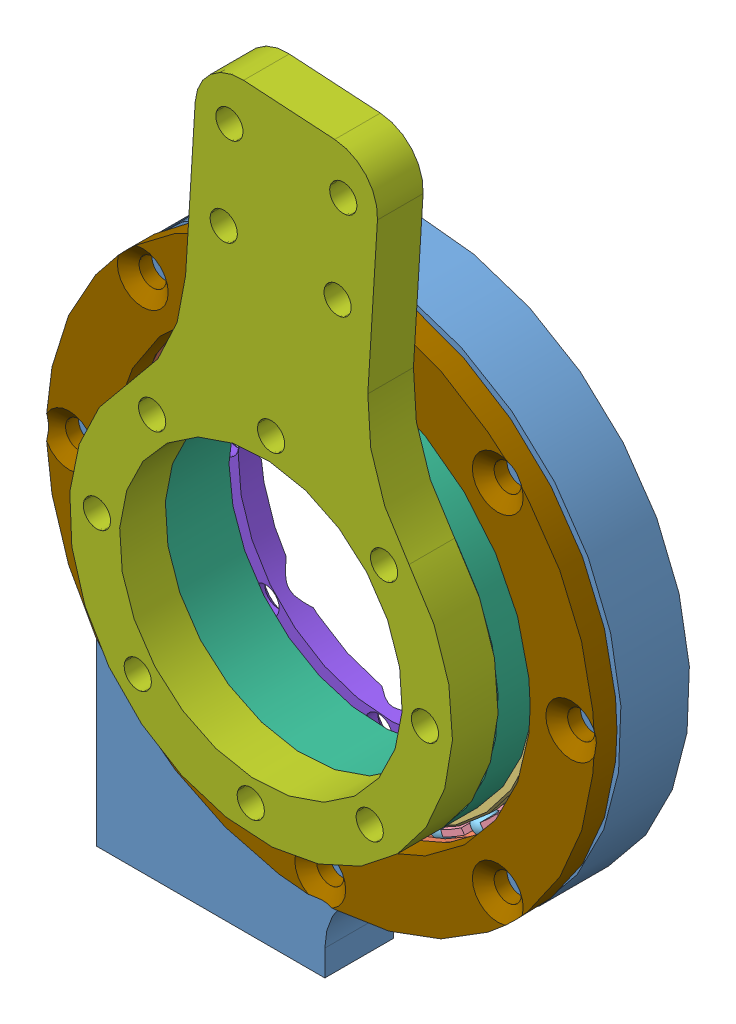
SolidWorks assembly shoulder-bearing-half, configuration otherside. Lengths in mm.
Overall size (78.52 115.83 21.59).
37 component instances, 9 part files, 14 mates.
Components (placement in the parent):
- a01-shoulder-base-1: a01-shoulder-base [otherside] at origin size (76.2 88.9 6.35)
- SW3dPS partNO- -KA020AR0-1: SW3dPS partNO- -KA020AR0 [KA020CP0] at (0 0 7.3406) x (-1 0 0) z (0 -1 0) size (63.5 6.35 63.5)
  - SW3dPS-KA - Radial Contact_KA OUTER CATALOG-1: SW3dPS-KA - Radial Contact_KA OUTER CATALOG [KA020002] at origin size (63.5 6.35 63.5)
  - SW3dPS-KA - Radial Contact_KA INNER CATALOG-1: SW3dPS-KA - Radial Contact_KA INNER CATALOG [KA020003] at origin size (55.52 6.35 55.52)
  - SW3dPS-KA - Radial Contact_KA SEPARATOR SAMPLE-1: SW3dPS-KA - Radial Contact_KA SEPARATOR SAMPLE [KA020] at origin size (60.31 5.28 60.41)
    - SW3dPS-KA - Radial Contact_KA SEPARATOR SAMPLE-1: SW3dPS-KA - Radial Contact_KA SEPARATOR SAMPLE [02510020] at origin size (57.94 5.28 57.94)
    - SW3dPS-KA - Radial Contact_KA BALL-1: SW3dPS-KA - Radial Contact_KA BALL [KA020] at origin size (3.17 3.17 3.17)
    - SW3dPS-KA - Radial Contact_KA BALL-2: SW3dPS-KA - Radial Contact_KA BALL [KA020] x (0.973045 0 0.230616) z (-0.230616 0 0.973045) size (3.17 3.17 3.17)
    - SW3dPS-KA - Radial Contact_KA BALL-3: SW3dPS-KA - Radial Contact_KA BALL [KA020] x (0.893633 0 0.448799) z (-0.448799 0 0.893633) size (3.17 3.17 3.17)
    - SW3dPS-KA - Radial Contact_KA BALL-4: SW3dPS-KA - Radial Contact_KA BALL [KA020] x (0.766044 0 0.642788) z (-0.642788 0 0.766044) size (3.17 3.17 3.17)
    - SW3dPS-KA - Radial Contact_KA BALL-5: SW3dPS-KA - Radial Contact_KA BALL [KA020] x (0.597159 0 0.802123) z (-0.802123 0 0.597159) size (3.17 3.17 3.17)
    - SW3dPS-KA - Radial Contact_KA BALL-6: SW3dPS-KA - Radial Contact_KA BALL [KA020] x (0.39608 0 0.918216) z (-0.918216 0 0.39608) size (3.17 3.17 3.17)
    - SW3dPS-KA - Radial Contact_KA BALL-7: SW3dPS-KA - Radial Contact_KA BALL [KA020] x (0.173648 0 0.984808) z (-0.984808 0 0.173648) size (3.17 3.17 3.17)
    - SW3dPS-KA - Radial Contact_KA BALL-8: SW3dPS-KA - Radial Contact_KA BALL [KA020] x (-0.058145 0 0.998308) z (-0.998308 0 -0.058145) size (3.17 3.17 3.17)
    - SW3dPS-KA - Radial Contact_KA BALL-9: SW3dPS-KA - Radial Contact_KA BALL [KA020] x (-0.286803 0 0.95799) z (-0.95799 0 -0.286803) size (3.17 3.17 3.17)
    - SW3dPS-KA - Radial Contact_KA BALL-10: SW3dPS-KA - Radial Contact_KA BALL [KA020] x (-0.5 0 0.866025) z (-0.866025 0 -0.5) size (3.17 3.17 3.17)
    - SW3dPS-KA - Radial Contact_KA BALL-11: SW3dPS-KA - Radial Contact_KA BALL [KA020] x (-0.686242 0 0.727374) z (-0.727374 0 -0.686242) size (3.17 3.17 3.17)
    - SW3dPS-KA - Radial Contact_KA BALL-12: SW3dPS-KA - Radial Contact_KA BALL [KA020] x (-0.835488 0 0.549509) z (-0.549509 0 -0.835488) size (3.17 3.17 3.17)
    - SW3dPS-KA - Radial Contact_KA BALL-13: SW3dPS-KA - Radial Contact_KA BALL [KA020] x (-0.939693 0 0.34202) z (-0.34202 0 -0.939693) size (3.17 3.17 3.17)
    - SW3dPS-KA - Radial Contact_KA BALL-14: SW3dPS-KA - Radial Contact_KA BALL [KA020] x (-0.993238 0 0.116093) z (-0.116093 0 -0.993238) size (3.17 3.17 3.17)
    - SW3dPS-KA - Radial Contact_KA BALL-15: SW3dPS-KA - Radial Contact_KA BALL [KA020] x (-0.993238 0 -0.116093) z (0.116093 0 -0.993238) size (3.17 3.17 3.17)
    - SW3dPS-KA - Radial Contact_KA BALL-16: SW3dPS-KA - Radial Contact_KA BALL [KA020] x (-0.939693 0 -0.34202) z (0.34202 0 -0.939693) size (3.17 3.17 3.17)
    - SW3dPS-KA - Radial Contact_KA BALL-17: SW3dPS-KA - Radial Contact_KA BALL [KA020] x (-0.835488 0 -0.549509) z (0.549509 0 -0.835488) size (3.17 3.17 3.17)
    - SW3dPS-KA - Radial Contact_KA BALL-18: SW3dPS-KA - Radial Contact_KA BALL [KA020] x (-0.686242 0 -0.727374) z (0.727374 0 -0.686242) size (3.17 3.17 3.17)
    - SW3dPS-KA - Radial Contact_KA BALL-19: SW3dPS-KA - Radial Contact_KA BALL [KA020] x (-0.5 0 -0.866025) z (0.866025 0 -0.5) size (3.17 3.17 3.17)
    - SW3dPS-KA - Radial Contact_KA BALL-20: SW3dPS-KA - Radial Contact_KA BALL [KA020] x (-0.286803 0 -0.95799) z (0.95799 0 -0.286803) size (3.17 3.17 3.17)
    - SW3dPS-KA - Radial Contact_KA BALL-21: SW3dPS-KA - Radial Contact_KA BALL [KA020] x (-0.058145 0 -0.998308) z (0.998308 0 -0.058145) size (3.17 3.17 3.17)
    - SW3dPS-KA - Radial Contact_KA BALL-22: SW3dPS-KA - Radial Contact_KA BALL [KA020] x (0.173648 0 -0.984808) z (0.984808 0 0.173648) size (3.17 3.17 3.17)
    - SW3dPS-KA - Radial Contact_KA BALL-23: SW3dPS-KA - Radial Contact_KA BALL [KA020] x (0.39608 0 -0.918216) z (0.918216 0 0.39608) size (3.17 3.17 3.17)
    - SW3dPS-KA - Radial Contact_KA BALL-24: SW3dPS-KA - Radial Contact_KA BALL [KA020] x (0.597159 0 -0.802123) z (0.802123 0 0.597159) size (3.17 3.17 3.17)
    - SW3dPS-KA - Radial Contact_KA BALL-25: SW3dPS-KA - Radial Contact_KA BALL [KA020] x (0.766044 0 -0.642788) z (0.642788 0 0.766044) size (3.17 3.17 3.17)
    - SW3dPS-KA - Radial Contact_KA BALL-26: SW3dPS-KA - Radial Contact_KA BALL [KA020] x (0.893633 0 -0.448799) z (0.448799 0 0.893633) size (3.17 3.17 3.17)
    - SW3dPS-KA - Radial Contact_KA BALL-27: SW3dPS-KA - Radial Contact_KA BALL [KA020] x (0.973045 0 -0.230616) z (0.230616 0 0.973045) size (3.17 3.17 3.17)
- a02-inside-bearing-1: a02-inside-bearing [Default] at (0 0 15.24) x (0 0 1) z (-0.061832 -0.998087 0)
- a04-shoulder-output-1: a04-shoulder-output [Default] at (0 0 21.59) x (0.998087 -0.061832 0) z (0 0 -1)
- a08-innerbearing-ring-1: a08-innerbearing-ring [Default] at (0 0 3.81) x (-0.662032 0.749475 0) z (0 0 -1)
- a07-outerbearing-ring-1: a07-outerbearing-ring [Default] at (0 0 10.16)
Mates (geometry in assembly coordinates):
- Coincident1: coincident anti-aligned: plane of a01-shoulder-base-1; plane of SW3dPS partNO- -KA020AR0-1/SW3dPS-KA - Radial Contact_KA OUTER CATALOG-1
- Concentric1: concentric aligned: cylinder of a01-shoulder-base-1; cylinder of ?
- Coincident2: coincident anti-aligned: plane of ?; plane of a02-inside-bearing-1 through (-26.619 1.649 10.16) normal (0 0 -1)
- Concentric2: concentric anti-aligned: cylinder of ?; cylinder of a02-inside-bearing-1
- Concentric3: concentric aligned: cylinder of a02-inside-bearing-1; cylinder of a04-shoulder-output-1
- Coincident3: coincident anti-aligned: plane of a02-inside-bearing-1 through (-20.9149 1.2957 15.24) normal (0 0 1); plane of a04-shoulder-output-1 through (0 0 15.24) normal (0 0 -1)
- Parallel1: parallel anti-aligned: plane of a01-shoulder-base-1; plane of ?
- Concentric4: concentric aligned: cylinder of a02-inside-bearing-1; cylinder of a04-shoulder-output-1
- Concentric5: concentric aligned: cylinder of a02-inside-bearing-1; cylinder of a08-innerbearing-ring-1
- Concentric6: concentric aligned: cylinder of a02-inside-bearing-1; cylinder of a08-innerbearing-ring-1
- Concentric7: concentric aligned: cylinder of a01-shoulder-base-1; cylinder of a07-outerbearing-ring-1
- Coincident4: coincident anti-aligned: plane of a07-outerbearing-ring-1 through (0 0 10.16) normal (0 0 -1); plane of ?
- Coincident5: coincident anti-aligned: plane of SW3dPS partNO- -KA020AR0-1/SW3dPS-KA - Radial Contact_KA OUTER CATALOG-1; plane of a08-innerbearing-ring-1 through (0 0 3.81) normal (0 0 1)
- Concentric8: concentric aligned: cylinder of a01-shoulder-base-1; cylinder of a07-outerbearing-ring-1
